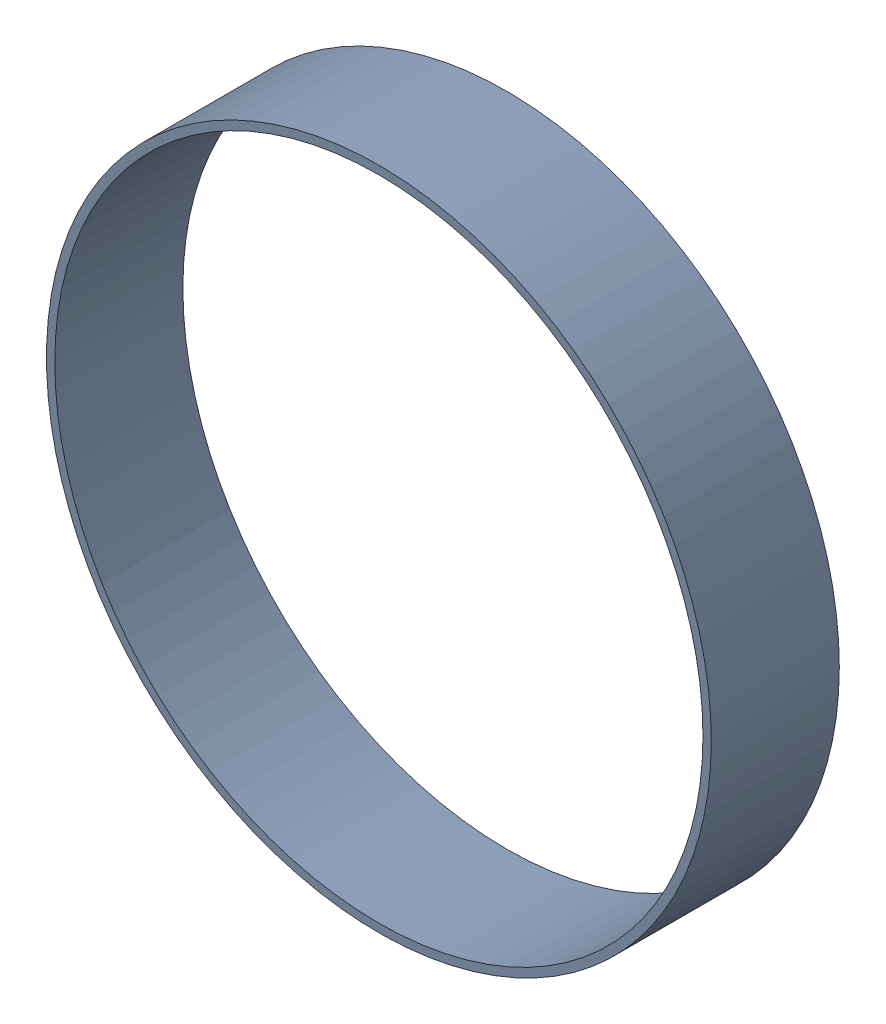
SolidWorks assembly Pad U1-5(7.028mm,59.438mm) on Multi-Layer, configuration Predeterminado. Lengths in mm.
Overall size (2.03 2.03 0.39).
2 component instances, 1 part files, 0 mates.
Components (placement in the parent):
- Pad Hole-3-1: Pad Hole-3 [Predeterminado] at (7.0284 59.4378 -0.4013) size (2.03 2.03 0.39)
  - Pad Hole-Part-1-3-1: Pad Hole-Part-1-3 [Predeterminado] at origin size (2.03 2.03 0.39)
